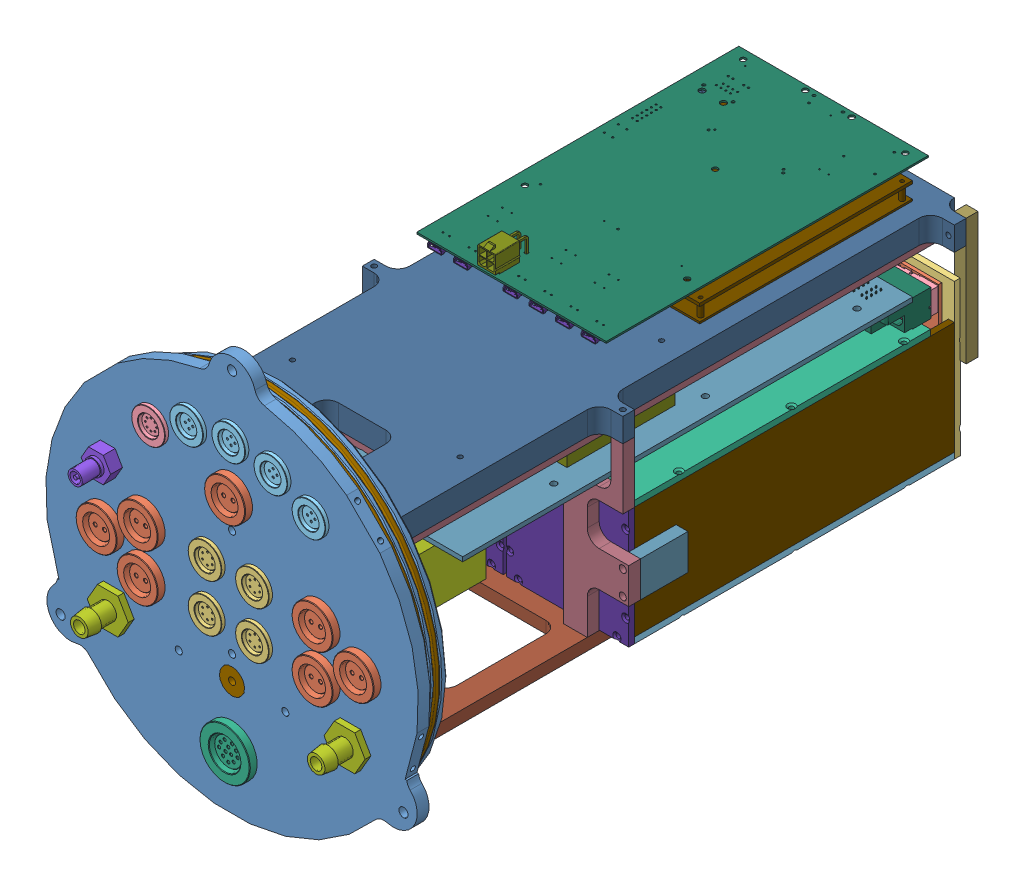
SolidWorks assembly internals, configuration Default. Lengths in mm.
Overall size (200.03 212.72 348.62).
189 component instances, 49 part files, 118 mates.
Components (placement in the parent):
- back_endcap-1: back_endcap [Default] at (-10.7708 -8.7171 12.0542) size (200.03 212.72 22.23)
- 104-DEE Connector (2 pin)-1: 104-DEE Connector (2 pin) [Default] at (36.1252 -21.4171 18.4042) size (22 22 24)
- 104-DEE Connector (2 pin)-2: 104-DEE Connector (2 pin) [Default] at (36.1252 3.9829 18.4042) size (22 22 24)
- 104-DEE Connector (2 pin)-3: 104-DEE Connector (2 pin) [Default] at (58.1223 -8.7171 18.4042) size (22 22 24)
- 104-DEE Connector (2 pin)-4: 104-DEE Connector (2 pin) [Default] at (-57.6668 3.9829 18.4042) size (22 22 24)
- 104-DEE Connector (2 pin)-5: 104-DEE Connector (2 pin) [Default] at (-57.6668 -21.4171 18.4042) size (22 22 24)
- 104-DEE Connector (2 pin)-6: 104-DEE Connector (2 pin) [Default] at (-79.6638 -8.7171 18.4042) size (22 22 24)
- 103-DEE Connector (6 pin)-1: 103-DEE Connector (6 pin) [Default] at (-23.4708 3.9829 18.4042) size (19.63 18 21)
- 103-DEE Connector (6 pin)-2: 103-DEE Connector (6 pin) [Default] at (1.9292 3.9829 18.4042) size (19.63 18 21)
- 103-DEE Connector (6 pin)-3: 103-DEE Connector (6 pin) [Default] at (-23.4708 -21.4171 18.4042) size (19.63 18 21)
- 103-DEE Connector (6 pin)-4: 103-DEE Connector (6 pin) [Default] at (1.9292 -21.4171 18.4042) size (19.63 18 21)
- 103-DEE Connector (8 pin)-1: 103-DEE Connector (8 pin) [Default] at (-53.7619 51.0956 18.4042) size (19.63 18 21)
- 103-DEE Connector (4 pin)-1: 103-DEE Connector (4 pin) [Default] at (32.2204 51.0956 18.4042) size (19.63 18 18)
- 103-DEE Connector (4 pin)-2: 103-DEE Connector (4 pin) [Default] at (11.8123 61.3957 18.4042) size (19.63 18 18)
- 103-DEE Connector (4 pin)-3: 103-DEE Connector (4 pin) [Default] at (-33.3539 61.3957 18.4042) size (19.63 18 18)
- 103-DEE Connector (4 pin)-4: 103-DEE Connector (4 pin) [Default] at (-10.7708 64.9429 18.4042) size (19.63 18 18)
- 104-DEE Connector (2 pin)-7: 104-DEE Connector (2 pin) [Default] at (-10.7708 39.2402 18.4042) size (22 22 24)
- 105-DEE Connector-1: 105-DEE Connector [Default] at (-10.7708 -78.5671 18.4042) size (28.87 27 29)
- endcap_coolant_plugs-1: endcap_coolant_plugs [Default] at (-74.2708 -44.2771 21.5792) x (0.866025 -0.5 0) z (-0.5 -0.866025 0) size (19.05 50.16 22)
- endcap_coolant_plugs-2: endcap_coolant_plugs [Default] at (52.7292 -44.2771 21.5792) x (0.866025 -0.5 0) z (-0.5 -0.866025 0) size (19.05 50.16 22)
- schradervalve-1: schradervalve [Default] at (-77.4458 23.0329 26.3417) size (15.84 13.72 33.34)
- hull o-ring-1: hull o-ring [Default] at (-10.7708 -8.7171 7.6583) size (187.32 187.32 3.17)
- hull o-ring-2: hull o-ring [Default] at (-10.7708 -8.7171 1.8023) size (187.32 187.32 3.17)
- cooling_base2-1: cooling_base2 [Default] at (-10.7708 41.1939 -159.3958) x (-1 0 0) z (0 0 1) size (139.7 12.7 323.85)
- backplane-1: backplane [Default] at (-10.7721 60.2939 -184.7958) x (0 0 1) z (-1 0 0) size (292.1 21.3 114.3) (hidden)
- cooling_mount_left-4: cooling_mount_left [Default] at (-48.8708 25.3189 8.8792) x (-1 0 0) z (0 0 1) size (38.1 12.7 12.7)
- cooling_mount_right-3: cooling_mount_right [Default] at (27.3292 25.3189 8.8792) x (-1 0 0) z (0 0 1) size (38.1 12.7 12.7)
- cooling_lid-1: cooling_lid [Default] at (-10.7708 28.4939 -159.3958) x (-1 0 0) z (0 0 1) size (114.3 3.39 304.8)
- powerboard-2: powerboard [Default] at (-16.1767 8.5021 -175.4049) x (0 0 1) z (1 0 0) size (251.08 27.63 127)
  - powerboard-1: powerboard [Default] at (-6.0888 -4.1168 5.4059) size (241.3 2.36 127)
  - molex_connector_876061001-1: molex_connector_876061001 [Default] at (-117.4688 -3.7646 44.4509) x (0 0 1) z (-1 0 0) size (48.91 16 23.62)
  - molex_connector_876061001-2: molex_connector_876061001 [Default] at (-117.4688 -3.7646 -22.8591) x (0 0 1) z (-1 0 0) size (48.91 16 23.62)
  - DC-DC-1: DC-DC [Default] at (35.2707 -4.1168 24.9416) x (1 0 0) z (0 0 -1) size (57.9 12.7 61)
- battbox-1: battbox [Default] at (51.374 -76.7142 -209.1378) x (-1 0 0) z (0 0 -1) size (65.53 82.72 178.14)
  - battbox_back-1: battbox_back [Default] at (28.2408 39.3364 -78.3001) x (-1 0 0) z (0 -1 0) size (65.53 3.34 66.67)
  - battbox_side-1: battbox_side [Default] at (-1.3502 39.3364 7.4249) x (0 1 0) z (0 0 1) size (60.32 3.17 171.45)
  - battbox_side-2: battbox_side [Default] at (57.8318 39.3364 7.4249) x (0 -1 0) z (0 0 1) size (60.32 3.17 171.45)
  - LiPoBattery-3.7V-1: LiPoBattery-3.7V [Default] at (28.1498 14.4989 -78.3001) x (0 -1 0) z (0 0 1) size (10 59 155)
  - LiPoBattery-3.7V-2: LiPoBattery-3.7V [Default] at (28.1498 24.4989 -78.3001) x (0 1 0) z (0 0 1) size (10 59 155)
  - LiPoBattery-3.7V-3: LiPoBattery-3.7V [Default] at (28.1498 54.4989 -78.3001) x (0 1 0) z (0 0 1) size (10 59 155)
  - LiPoBattery-3.7V-4: LiPoBattery-3.7V [Default] at (28.1498 34.4989 -78.3001) x (0 1 0) z (0 0 1) size (10 59 155)
  - LiPoBattery-3.7V-5: LiPoBattery-3.7V [Default] at (28.1498 44.4989 -78.3001) x (0 1 0) z (0 0 1) size (10 59 155)
  - LiPoBattery-3.7V-6: LiPoBattery-3.7V [Default] at (28.1498 64.4989 -78.3001) x (0 1 0) z (0 0 1) size (10 59 155)
  - battery_board-1: battery_board [Default] at (28.1498 47.6739 87.8159) size (59 79 1.78)
  - battbox_front-1: battbox_front [Default] at (28.2408 39.3364 93.1499) x (1 0 0) z (0 -1 0) size (65.53 3.34 82.55)
  - molex_connector_876951001-1: molex_connector_876951001 [Default] at (23.0998 81.4859 81.4659) x (1 0 0) z (0 1 0) size (48.9 20.45 12.09)
  - battbox_base-3: battbox_base [Default] at (28.2408 9.1739 7.4249) x (-1 0 0) z (0 0 1) size (65.53 3.34 171.45)
  - battbox_top-2: battbox_top [Default] at (28.2408 69.4989 1.0749) size (65.53 3.34 158.75)
- battbox-2: battbox [Default] at (-15.936 -76.7142 -209.1378) x (-1 0 0) z (0 0 -1) size (65.53 82.72 178.14)
  - battbox_back-1: battbox_back [Default] at (28.2408 39.3364 -78.3001) x (-1 0 0) z (0 -1 0) size (65.53 3.34 66.67)
  - battbox_side-1: battbox_side [Default] at (-1.3502 39.3364 7.4249) x (0 1 0) z (0 0 1) size (60.32 3.17 171.45)
  - battbox_side-2: battbox_side [Default] at (57.8318 39.3364 7.4249) x (0 -1 0) z (0 0 1) size (60.32 3.17 171.45)
  - LiPoBattery-3.7V-1: LiPoBattery-3.7V [Default] at (28.1498 14.4989 -78.3001) x (0 -1 0) z (0 0 1) size (10 59 155)
  - LiPoBattery-3.7V-2: LiPoBattery-3.7V [Default] at (28.1498 24.4989 -78.3001) x (0 1 0) z (0 0 1) size (10 59 155)
  - LiPoBattery-3.7V-3: LiPoBattery-3.7V [Default] at (28.1498 54.4989 -78.3001) x (0 1 0) z (0 0 1) size (10 59 155)
  - LiPoBattery-3.7V-4: LiPoBattery-3.7V [Default] at (28.1498 34.4989 -78.3001) x (0 1 0) z (0 0 1) size (10 59 155)
  - LiPoBattery-3.7V-5: LiPoBattery-3.7V [Default] at (28.1498 44.4989 -78.3001) x (0 1 0) z (0 0 1) size (10 59 155)
  - LiPoBattery-3.7V-6: LiPoBattery-3.7V [Default] at (28.1498 64.4989 -78.3001) x (0 1 0) z (0 0 1) size (10 59 155)
  - battery_board-1: battery_board [Default] at (28.1498 47.6739 87.8159) size (59 79 1.78)
  - battbox_front-1: battbox_front [Default] at (28.2408 39.3364 93.1499) x (1 0 0) z (0 -1 0) size (65.53 3.34 82.55)
  - molex_connector_876951001-1: molex_connector_876951001 [Default] at (23.0998 81.4859 81.4659) x (1 0 0) z (0 1 0) size (48.9 20.45 12.09)
  - battbox_base-3: battbox_base [Default] at (28.2408 9.1739 7.4249) x (-1 0 0) z (0 0 1) size (65.53 3.34 171.45)
  - battbox_top-2: battbox_top [Default] at (28.2408 69.4989 1.0749) size (65.53 3.34 158.75)
- pump-2: pump [Default] at (-44.8873 -70.9471 -90.7364) size (61.12 37.5 86.12)
- coolant_plugs-1: coolant_plugs [Default] at (25.7417 22.1439 -24.7758) x (-0.99483 0 0.101556) z (0.101556 0 0.99483) size (15.95 24.13 18.41)
- coolant_plugs-2: coolant_plugs [Default] at (-47.2833 22.1439 -24.7758) x (-0.997358 0 0.072637) z (0.072637 0 0.997358) size (15.95 24.13 18.41)
- pressure sensor-1: pressure sensor [Default] at (-10.7708 -46.8171 7.7362) x (0.998621 0.052498 0) z (0 0 1) size (18.33 15.88 86.31)
- half inch wide L bracket-1: half inch wide L bracket [Default] at (33.6792 -70.9471 12.0542) size (12.7 15.88 19.05)
- half inch wide L bracket-2: half inch wide L bracket [Default] at (-55.2208 -70.9471 12.0542) size (12.7 15.88 19.05)
- battery mount base-1: battery mount base [Default] at (-10.7708 -77.2971 -149.8708) x (0 0 -1) z (1 0 0) size (323.85 6.35 101.6)
- batter mount front-1: batter mount front [Default] at (-10.7708 -14.8766 -311.7958) x (0 1 0) z (1 0 0) size (118.49 6.35 139.7)
- batter mount back-1: batter mount back [Default] at (-10.7708 -21.2266 -127.6458) x (0 1 0) z (1 0 0) size (99.44 6.35 146.05)
- batter holding block-1: batter holding block [Default] at (-77.4458 -36.0221 -140.3458) x (0 0 1) z (0 -1 0) size (25.4 6.35 19.05)
- batter holding block-2: batter holding block [Default] at (62.2542 -36.0221 -140.3458) x (0 0 1) z (0 -1 0) size (25.4 6.35 19.05)
- batter holding block-3: batter holding block [Default] at (-10.7708 -4.1451 -140.3458) x (0 0 1) z (-1 0 0) size (25.4 6.35 19.05)
- PCB-1: PCB [Default] at (113.5642 61.2905 -17.2808) x (0 0 -1) z (0 1 0) size (172.72 101.6 16.27)
  - Revised Board-1: Revised Board [Default] at (0 0 -0.8966) size (172.72 101.6 0.91)
  - FB5-1: FB5 [Default] at origin
    - 506292128-1: 506292128 [Default] at (256.667 117.094 0.0127)
      - Extruded-1: Extruded [Default] at origin (suppressed, hidden)
  - SATA1-1: SATA1 [Default] at origin size (56.51 47.45 7.82) (suppressed, hidden)
  - FB12-1: FB12 [Default] at origin
    - 506292128-1: 506292128 [Default] at (285.75 103.124 0.0127)
      - Extruded-1: Extruded [Default] at origin (suppressed, hidden)
  - POWER-1: POWER [Default] at origin size (19.94 10 15)
    - 039300040-1: 039300040 [Default] at (114.9497 138.4306 0.0127) x (0 -1 0) z (-1 0 0) size (10 15 19.94)
      - Open CASCADE STEP translator 6.2 18.5.1.1-1: Open CASCADE STEP translator 6.2 18.5.1.1 [Default] at origin size (10 15 19.94)
  - BATTERY-1: BATTERY [Default] at origin
    - 506290848-1: 506290848 [Default] at (264.16 79.248 0.0127)
      - Extruded_1-1: Extruded_1 [Default] at origin (suppressed, hidden)
    - 506290720-1: 506290720 [Default] at (264.16 78.994 0.0127)
      - Extruded_2-1: Extruded_2 [Default] at origin (suppressed, hidden)
    - 506290592-1: 506290592 [Default] at (264.16 87.63 7.9629)
      - Extruded_3-1: Extruded_3 [Default] at origin (suppressed, hidden)
    - 506291360-1: 506291360 [Default] at (264.16 90.17 0.0127)
      - Extruded_4-1: Extruded_4 [Default] at origin (suppressed, hidden)
    - 506291232-1: 506291232 [Default] at (264.16 90.17 0.0127)
      - Extruded_5-1: Extruded_5 [Default] at origin (suppressed, hidden)
  - Reset-1: Reset [Default] at origin size (6.25 6.25 5) (suppressed, hidden)
  - FB6-1: FB6 [Default] at origin
    - 506292128-1: 506292128 [Default] at (261.747 117.094 0.0127)
      - Extruded-1: Extruded [Default] at origin (suppressed, hidden)
  - FB7-1: FB7 [Default] at origin
    - 506292128-1: 506292128 [Default] at (266.827 117.094 0.0127)
      - Extruded-1: Extruded [Default] at origin (suppressed, hidden)
  - FB8-1: FB8 [Default] at origin
    - 506292128-1: 506292128 [Default] at (269.24 132.08 0.0127)
      - Extruded-1: Extruded [Default] at origin (suppressed, hidden)
  - FB9-1: FB9 [Default] at origin
    - 506292128-1: 506292128 [Default] at (264.16 139.7 0.0127)
      - Extruded-1: Extruded [Default] at origin (suppressed, hidden)
  - FB10-1: FB10 [Default] at origin
    - 506292128-1: 506292128 [Default] at (261.62 132.08 0.0127)
      - Extruded-1: Extruded [Default] at origin (suppressed, hidden)
  - FB11-1: FB11 [Default] at origin
    - 506292128-1: 506292128 [Default] at (256.54 132.08 0.0127)
      - Extruded-1: Extruded [Default] at origin (suppressed, hidden)
  - U1-1: U1 [Default] at origin size (3.9 8.65 1.75) (suppressed, hidden)
  - VGA1-1: VGA1 [Default] at origin size (22.01 30.8 16) (suppressed, hidden)
  - X1-1: X1 [Default] at origin
    - 506290976-1: 506290976 [Default] at (259.2025 158.75 0.0127)
      - Extruded_10-1: Extruded_10 [Default] at origin (suppressed, hidden)
  - FB1_1-1: FB1_1 [Default] at origin
    - 506292000-1: 506292000 [Default] at (132.08 80.01 -1.8466)
      - Extruded_11-1: Extruded_11 [Default] at origin (suppressed, hidden)
  - FB1_2-1: FB1_2 [Default] at origin
    - 506292000-1: 506292000 [Default] at (132.08 107.95 -1.8466)
      - Extruded_11-1: Extruded_11 [Default] at origin (suppressed, hidden)
  - FB1_3-1: FB1_3 [Default] at origin
    - 506291872-1: 506291872 [Default] at (132.08 148.59 -1.8466)
      - Extruded_12-1: Extruded_12 [Default] at origin (suppressed, hidden)
  - FB2_1-1: FB2_1 [Default] at origin
    - 506292000-1: 506292000 [Default] at (132.08 88.9 -1.8466)
      - Extruded_11-1: Extruded_11 [Default] at origin (suppressed, hidden)
  - FB2_2-1: FB2_2 [Default] at origin
    - 506291872-1: 506291872 [Default] at (132.08 116.84 -1.8466)
      - Extruded_12-1: Extruded_12 [Default] at origin (suppressed, hidden)
  - FB2_3-1: FB2_3 [Default] at origin
    - 506291872-1: 506291872 [Default] at (132.08 156.21 -1.8466)
      - Extruded_12-1: Extruded_12 [Default] at origin (suppressed, hidden)
  - FB3_1-1: FB3_1 [Default] at origin
    - 506292000-1: 506292000 [Default] at (132.08 93.98 -1.8466)
      - Extruded_11-1: Extruded_11 [Default] at origin (suppressed, hidden)
  - FB3_2-1: FB3_2 [Default] at origin
    - 506291872-1: 506291872 [Default] at (132.08 121.92 -1.8466)
      - Extruded_12-1: Extruded_12 [Default] at origin (suppressed, hidden)
  - FB3_3-1: FB3_3 [Default] at origin
    - 506291872-1: 506291872 [Default] at (132.08 162.56 -1.8466)
      - Extruded_12-1: Extruded_12 [Default] at origin (suppressed, hidden)
  - FB4_1-1: FB4_1 [Default] at origin
    - 506292128-1: 506292128 [Default] at (128.27 100.33 -1.8466)
      - Extruded-1: Extruded [Default] at origin (suppressed, hidden)
  - FB4_2-1: FB4_2 [Default] at origin
    - 506291872-1: 506291872 [Default] at (132.08 129.54 -1.8466)
      - Extruded_12-1: Extruded_12 [Default] at origin (suppressed, hidden)
  - FB4_3-1: FB4_3 [Default] at origin
    - 506292000-1: 506292000 [Default] at (132.334 170.18 -1.8466)
      - Extruded_11-1: Extruded_11 [Default] at origin (suppressed, hidden)
  - IC1_1-1: IC1_1 [Default] at origin
    - 506291488-1: 506291488 [Default] at (154.94 101.6 -2.6266)
      - Extruded_13-1: Extruded_13 [Default] at origin (suppressed, hidden)
  - IC1_2-1: IC1_2 [Default] at origin
    - 506291488-1: 506291488 [Default] at (154.94 118.11 -2.6266)
      - Extruded_13-1: Extruded_13 [Default] at origin (suppressed, hidden)
  - IC1_3-1: IC1_3 [Default] at origin
    - 506291744-1: 506291744 [Default] at (158.75 156.21 -2.6266)
      - Extruded_14-1: Extruded_14 [Default] at origin (suppressed, hidden)
  - J1-1: J1 [Default] at origin size (9 9.9 4.47)
    - UX60-MB-5ST_1-1: UX60-MB-5ST_1 [Default] at (163.2375 87.52 43.1834) x (-1 0 0) z (0 -1 0) size (9 4.47 9.9)
      - ux60-mb-5sT-1: ux60-mb-5sT [Default] at (39.3275 -4.7664 57.125) x (0 0 -1) z (1 0 0) size (9.9 4.47 9)
  - J2-1: J2 [Default] at origin size (9 9.9 4.47)
    - UX60-MB-5ST_1-1: UX60-MB-5ST_1 [Default] at (163.2375 101.363 43.1834) x (-1 0 0) z (0 -1 0) size (9 4.47 9.9)
      - ux60-mb-5sT-1: ux60-mb-5sT [Default] at (39.3275 -4.7664 57.125) x (0 0 -1) z (1 0 0) size (9.9 4.47 9)
  - J3-1: J3 [Default] at origin size (9 9.9 4.47)
    - UX60-MB-5ST_1-1: UX60-MB-5ST_1 [Default] at (163.2375 115.46 43.1834) x (-1 0 0) z (0 -1 0) size (9 4.47 9.9)
      - ux60-mb-5sT-1: ux60-mb-5sT [Default] at (39.3275 -4.7664 57.125) x (0 0 -1) z (1 0 0) size (9.9 4.47 9)
  - J4-1: J4 [Default] at origin size (9 9.9 4.47)
    - UX60-MB-5ST_1-1: UX60-MB-5ST_1 [Default] at (163.2375 129.43 43.1834) x (-1 0 0) z (0 -1 0) size (9 4.47 9.9)
      - ux60-mb-5sT-1: ux60-mb-5sT [Default] at (39.3275 -4.7664 57.125) x (0 0 -1) z (1 0 0) size (9.9 4.47 9)
  - J5-1: J5 [Default] at origin size (9 9.9 4.47)
    - UX60-MB-5ST_1-1: UX60-MB-5ST_1 [Default] at (163.2375 156.1 43.1834) x (-1 0 0) z (0 -1 0) size (9 4.47 9.9)
      - ux60-mb-5sT-1: ux60-mb-5sT [Default] at (39.3275 -4.7664 57.125) x (0 0 -1) z (1 0 0) size (9.9 4.47 9)
  - J6-1: J6 [Default] at origin size (9 9.9 4.47)
    - UX60-MB-5ST_1-1: UX60-MB-5ST_1 [Default] at (163.2375 170.07 43.1834) x (-1 0 0) z (0 -1 0) size (9 4.47 9.9)
      - ux60-mb-5sT-1: ux60-mb-5sT [Default] at (39.3275 -4.7664 57.125) x (0 0 -1) z (1 0 0) size (9.9 4.47 9)
  - OR1-1: OR1 [Default] at origin
    - 506292384-1: 506292384 [Default] at (157.48 137.16 -1.9966)
      - Extruded_15-1: Extruded_15 [Default] at origin (suppressed, hidden)
- XTX-1: XTX [Default] at (-10.7708 50.7939 -241.9208) x (0 0 1) z (1 0 0) size (114 19.1 95)
Mates (geometry in assembly coordinates):
- Coincident1: coincident anti-aligned: plane of back_endcap-1 through (-10.7708 -8.7171 18.4042) normal (0 0 1); plane of 104-DEE Connector (2 pin)-4 through (-57.6668 3.9829 18.4042) normal (0 0 -1)
- Coincident2: coincident anti-aligned: plane of back_endcap-1 through (-10.7708 -8.7171 18.4042) normal (0 0 1); plane of 104-DEE Connector (2 pin)-2 through (36.1252 3.9829 18.4042) normal (0 0 -1)
- Coincident3: coincident anti-aligned: plane of back_endcap-1 through (-10.7708 -8.7171 18.4042) normal (0 0 1); plane of 104-DEE Connector (2 pin)-3 through (58.1223 -8.7171 18.4042) normal (0 0 -1)
- Coincident6: coincident anti-aligned: plane of back_endcap-1 through (-10.7708 -8.7171 18.4042) normal (0 0 1); plane of 104-DEE Connector (2 pin)-5 through (-57.6668 -21.4171 18.4042) normal (0 0 -1)
- Coincident7: coincident anti-aligned: plane of back_endcap-1 through (-10.7708 -8.7171 18.4042) normal (0 0 1); plane of 104-DEE Connector (2 pin)-6 through (-79.6638 -8.7171 18.4042) normal (0 0 -1)
- Coincident8: coincident anti-aligned: plane of back_endcap-1 through (-10.7708 -8.7171 18.4042) normal (0 0 1); plane of 104-DEE Connector (2 pin)-1 through (36.1252 -21.4171 18.4042) normal (0 0 -1)
- Concentric1: concentric aligned: cylinder of back_endcap-1 through (-79.6638 -8.7171 -3.8208) axis (0 0 1) radius 8.05; cylinder of 104-DEE Connector (2 pin)-6 through (-79.6638 -8.7171 -1.5958) axis (0 0 1) radius 8
- Concentric2: concentric aligned: cylinder of back_endcap-1 through (-57.6668 3.9829 -3.8208) axis (0 0 1) radius 8.05; cylinder of 104-DEE Connector (2 pin)-4 through (-57.6668 3.9829 -1.5958) axis (0 0 1) radius 8
- Concentric3: concentric aligned: cylinder of back_endcap-1 through (-57.6668 -21.4171 -3.8208) axis (0 0 1) radius 8.05; cylinder of 104-DEE Connector (2 pin)-5 through (-57.6668 -21.4171 -1.5958) axis (0 0 1) radius 8
- Concentric4: concentric aligned: cylinder of back_endcap-1 through (36.1252 -21.4171 -3.8208) axis (0 0 1) radius 8.05; cylinder of 104-DEE Connector (2 pin)-1 through (36.1252 -21.4171 -1.5958) axis (0 0 1) radius 8
- Concentric5: concentric aligned: cylinder of back_endcap-1 through (36.1252 3.9829 -3.8208) axis (0 0 1) radius 8.05; cylinder of 104-DEE Connector (2 pin)-2 through (36.1252 3.9829 -1.5958) axis (0 0 1) radius 8
- Concentric6: concentric aligned: cylinder of back_endcap-1 through (58.1223 -8.7171 -3.8208) axis (0 0 1) radius 8.05; cylinder of 104-DEE Connector (2 pin)-3 through (58.1223 -8.7171 -1.5958) axis (0 0 1) radius 8
- Parallel1: parallel aligned: plane of 104-DEE Connector (2 pin)-2 through (30.6404 -5.5171 4.4042) normal (0 -1 0); plane of 104-DEE Connector (2 pin)-4 through (-63.1516 -5.5171 4.4042) normal (0 -1 0)
- Parallel2: parallel aligned: plane of 104-DEE Connector (2 pin)-5 through (-63.1516 -30.9171 4.4042) normal (0 -1 0); plane of 104-DEE Connector (2 pin)-6 through (-85.1487 -18.2171 4.4042) normal (0 -1 0)
- Parallel3: parallel aligned: plane of 104-DEE Connector (2 pin)-4 through (-63.1516 -5.5171 4.4042) normal (0 -1 0); plane of 104-DEE Connector (2 pin)-6 through (-85.1487 -18.2171 4.4042) normal (0 -1 0)
- Parallel4: parallel aligned: plane of 104-DEE Connector (2 pin)-1 through (30.6404 -30.9171 4.4042) normal (0 -1 0); plane of 104-DEE Connector (2 pin)-3 through (52.6375 -18.2171 4.4042) normal (0 -1 0)
- Parallel5: parallel aligned: plane of 104-DEE Connector (2 pin)-2 through (30.6404 -5.5171 4.4042) normal (0 -1 0); plane of 104-DEE Connector (2 pin)-3 through (52.6375 -18.2171 4.4042) normal (0 -1 0)
- Perpendicular1: perpendicular: line of back_endcap-1 through (-10.7708 -8.7171 18.4042) axis (0 1 0); line of 104-DEE Connector (2 pin)-2 through (41.6101 -5.5171 7.4042) axis (-1 0 0)
- Coincident16: coincident anti-aligned: plane of back_endcap-1 through (-10.7708 -8.7171 18.4042) normal (0 0 1); plane of 103-DEE Connector (6 pin)-2 through (1.9292 3.9829 18.4042) normal (0 0 -1)
- Coincident17: coincident anti-aligned: plane of back_endcap-1 through (-10.7708 -8.7171 18.4042) normal (0 0 1); plane of 103-DEE Connector (6 pin)-1 through (-23.4708 3.9829 18.4042) normal (0 0 -1)
- Coincident18: coincident anti-aligned: plane of back_endcap-1 through (-10.7708 -8.7171 18.4042) normal (0 0 1); plane of 103-DEE Connector (6 pin)-3 through (-23.4708 -21.4171 18.4042) normal (0 0 -1)
- Coincident19: coincident anti-aligned: plane of back_endcap-1 through (-10.7708 -8.7171 18.4042) normal (0 0 1); plane of 103-DEE Connector (6 pin)-4 through (1.9292 -21.4171 18.4042) normal (0 0 -1)
- Concentric7: concentric aligned: cylinder of back_endcap-1 through (1.9292 3.9829 -3.8208) axis (0 0 1) radius 7.05; cylinder of 103-DEE Connector (6 pin)-2 through (1.9292 3.9829 -0.5958) axis (0 0 1) radius 7
- Concentric8: concentric aligned: cylinder of back_endcap-1 through (-23.4708 3.9829 -3.8208) axis (0 0 1) radius 7.05; cylinder of 103-DEE Connector (6 pin)-1 through (-23.4708 3.9829 -0.5958) axis (0 0 1) radius 7
- Concentric9: concentric aligned: cylinder of back_endcap-1 through (-23.4708 -21.4171 -3.8208) axis (0 0 1) radius 7.05; cylinder of 103-DEE Connector (6 pin)-3 through (-23.4708 -21.4171 -0.5958) axis (0 0 1) radius 7
- Concentric10: concentric aligned: cylinder of back_endcap-1 through (1.9292 -21.4171 -3.8208) axis (0 0 1) radius 7.05; cylinder of 103-DEE Connector (6 pin)-4 through (1.9292 -21.4171 -0.5958) axis (0 0 1) radius 7
- Parallel6: parallel aligned: plane of 103-DEE Connector (6 pin)-1 through (-28.3783 -4.5171 3.4042) normal (0 -1 0); plane of 103-DEE Connector (6 pin)-2 through (-2.9783 -4.5171 3.4042) normal (0 -1 0)
- Parallel7: parallel aligned: plane of 103-DEE Connector (6 pin)-3 through (-28.3783 -29.9171 3.4042) normal (0 -1 0); plane of 103-DEE Connector (6 pin)-4 through (-2.9783 -29.9171 3.4042) normal (0 -1 0)
- Parallel8: parallel: plane of 103-DEE Connector (6 pin)-1 through (-28.3783 -4.5171 3.4042) normal (0 -1 0); line of 103-DEE Connector (6 pin)-3 through (-18.5633 -29.9171 3.4042) axis (-1 0 0)
- Parallel9: parallel aligned: plane of 104-DEE Connector (2 pin)-4 through (-63.1516 -5.5171 4.4042) normal (0 -1 0); plane of 103-DEE Connector (6 pin)-1 through (-28.3783 -4.5171 3.4042) normal (0 -1 0)
- Coincident24: coincident anti-aligned: plane of back_endcap-1 through (-10.7708 -8.7171 18.4042) normal (0 0 1); plane of 103-DEE Connector (8 pin)-1 through (-53.7619 51.0956 18.4042) normal (0 0 -1)
- Concentric11: concentric aligned: cylinder of back_endcap-1 through (-53.7619 51.0956 -3.8208) axis (0 0 1) radius 7.05; cylinder of 103-DEE Connector (8 pin)-1 through (-53.7619 51.0956 -0.5958) axis (0 0 1) radius 7
- Parallel10: parallel aligned: plane of 103-DEE Connector (4 pin)-1 through (37.1278 59.5956 6.4042) normal (0 1 0); plane of 103-DEE Connector (4 pin)-2 through (16.7198 69.8957 6.4042) normal (0 1 0)
- Parallel11: parallel aligned: plane of 103-DEE Connector (4 pin)-2 through (16.7198 69.8957 6.4042) normal (0 1 0); plane of 103-DEE Connector (4 pin)-3 through (-28.4464 69.8957 6.4042) normal (0 1 0)
- Parallel12: parallel aligned: plane of 103-DEE Connector (4 pin)-3 through (-28.4464 69.8957 6.4042) normal (0 1 0); plane of 103-DEE Connector (4 pin)-4 through (-5.8633 73.4429 6.4042) normal (0 1 0)
- Parallel13: parallel aligned: plane of 104-DEE Connector (2 pin)-6 through (-74.179 0.7829 4.4042) normal (0 1 0); plane of 103-DEE Connector (4 pin)-4 through (-5.8633 73.4429 6.4042) normal (0 1 0)
- Concentric14: concentric aligned: cylinder of back_endcap-1 through (-33.3539 61.3957 -3.8208) axis (0 0 1) radius 7.05; cylinder of 103-DEE Connector (4 pin)-3 through (-33.3539 61.3957 2.4042) axis (0 0 1) radius 7
- Concentric15: concentric aligned: cylinder of back_endcap-1 through (11.8123 61.3957 -3.8208) axis (0 0 1) radius 7.05; cylinder of 103-DEE Connector (4 pin)-2 through (11.8123 61.3957 2.4042) axis (0 0 1) radius 7
- Concentric16: concentric aligned: cylinder of back_endcap-1 through (32.2204 51.0956 -3.8208) axis (0 0 1) radius 7.05; cylinder of 103-DEE Connector (4 pin)-1 through (32.2204 51.0956 2.4042) axis (0 0 1) radius 7
- Coincident29: coincident anti-aligned: plane of back_endcap-1 through (-10.7708 -8.7171 18.4042) normal (0 0 1); plane of 103-DEE Connector (4 pin)-2 through (11.8123 61.3957 18.4042) normal (0 0 -1)
- Coincident30: coincident anti-aligned: plane of back_endcap-1 through (-10.7708 -8.7171 18.4042) normal (0 0 1); plane of 103-DEE Connector (4 pin)-1 through (32.2204 51.0956 18.4042) normal (0 0 -1)
- Concentric17: concentric aligned: cylinder of back_endcap-1 through (-10.7708 64.9429 -3.8208) axis (0 0 1) radius 7.05; cylinder of 103-DEE Connector (4 pin)-4 through (-10.7708 64.9429 2.4042) axis (0 0 1) radius 7
- Coincident31: coincident anti-aligned: plane of back_endcap-1 through (-10.7708 -8.7171 18.4042) normal (0 0 1); plane of 103-DEE Connector (4 pin)-4 through (-10.7708 64.9429 18.4042) normal (0 0 -1)
- Parallel14: parallel: line of 104-DEE Connector (2 pin)-2 through (30.6404 13.4829 7.4042) axis (1 0 0); plane of 104-DEE Connector (2 pin)-7 through (-5.2859 48.7402 4.4042) normal (0 1 0)
- Concentric18: concentric aligned: cylinder of back_endcap-1 through (-10.7708 39.2402 -3.8208) axis (0 0 1) radius 8.05; cylinder of 104-DEE Connector (2 pin)-7 through (-10.7708 39.2402 -1.5958) axis (0 0 1) radius 8
- Coincident34: coincident anti-aligned: plane of back_endcap-1 through (-10.7708 -8.7171 18.4042) normal (0 0 1); plane of 104-DEE Connector (2 pin)-7 through (-10.7708 39.2402 18.4042) normal (0 0 -1)
- Concentric19: concentric aligned: cylinder of back_endcap-1 through (-10.7708 -78.5671 -3.8208) axis (0 0 1) radius 10.033; cylinder of 105-DEE Connector-1 through (-10.7708 -78.5671 -6.5958) axis (0 0 1) radius 10
- Coincident35: coincident anti-aligned: plane of back_endcap-1 through (-10.7708 -8.7171 18.4042) normal (0 0 1); plane of 105-DEE Connector-1 through (-10.7708 -78.5671 18.4042) normal (0 0 -1)
- Parallel15: parallel aligned: plane of 103-DEE Connector (6 pin)-3 through (-18.5633 -12.9171 3.4042) normal (0 1 0); plane of 105-DEE Connector-1 through (-3.5539 -66.0671 -0.5958) normal (0 1 0)
- Parallel16: parallel aligned: plane of 103-DEE Connector (6 pin)-2 through (6.8367 12.4829 3.4042) normal (0 1 0); plane of endcap_coolant_plugs-2 through (58.2285 -34.7521 18.4042) normal (0 1 0)
- Parallel17: parallel aligned: plane of 103-DEE Connector (6 pin)-3 through (-18.5633 -12.9171 3.4042) normal (0 1 0); plane of endcap_coolant_plugs-1 through (-68.7715 -34.7521 18.4042) normal (0 1 0)
- Concentric20: concentric anti-aligned: cylinder of back_endcap-1 through (-74.2708 -44.2771 -3.8208) axis (0 0 1) radius 5.588; cylinder of endcap_coolant_plugs-1 through (-74.2708 -44.2771 19.9917) axis (0 0 -1) radius 5.588
- Concentric21: concentric anti-aligned: cylinder of back_endcap-1 through (52.7292 -44.2771 -3.8208) axis (0 0 1) radius 5.588; cylinder of endcap_coolant_plugs-2 through (52.7292 -44.2771 19.9917) axis (0 0 -1) radius 5.588
- Coincident39: coincident anti-aligned: plane of back_endcap-1 through (-10.7708 -8.7171 18.4042) normal (0 0 1); plane of endcap_coolant_plugs-2 through (36.2314 -34.7521 18.4042) normal (0 0 -1)
- Coincident40: coincident anti-aligned: plane of back_endcap-1 through (-10.7708 -8.7171 18.4042) normal (0 0 1); plane of endcap_coolant_plugs-1 through (-90.7686 -34.7521 18.4042) normal (0 0 -1)
- Concentric22: concentric aligned: cone of back_endcap-1 through (-77.4458 23.0329 12.0542) axis (0 0 1); cylinder of schradervalve-1 through (-77.4458 23.0329 2.5292) axis (0 0 1) radius 4.9276
- Coincident41: coincident anti-aligned: plane of back_endcap-1 through (-10.7708 -8.7171 18.4042) normal (0 0 1); plane of schradervalve-1 through (-73.4863 29.8909 18.4042) normal (0 0 -1)
- Concentric23: concentric anti-aligned: cylinder of back_endcap-1 through (-10.7708 -8.7171 12.0542) axis (0 0 1) radius 91.1225; cylinder of hull o-ring-2 through (-10.7708 -8.7171 1.8023) axis (0 0 -1) radius 90.4875
- Concentric24: concentric anti-aligned: cylinder of back_endcap-1 through (-10.7708 -8.7171 12.0542) axis (0 0 1) radius 91.1225; cylinder of hull o-ring-1 through (-10.7708 -8.7171 7.6583) axis (0 0 -1) radius 90.4875
- Coincident42: coincident anti-aligned: plane of back_endcap-1 through (-10.7708 84.9454 9.2458) normal (0 0 -1); plane of hull o-ring-1 through (-10.7708 84.1834 9.2458) normal (0 0 1)
- Coincident43: coincident anti-aligned: plane of back_endcap-1 through (-10.7708 84.9454 3.3898) normal (0 0 -1); plane of hull o-ring-2 through (-10.7708 84.1834 3.3898) normal (0 0 1)
- Coincident44: coincident anti-aligned: plane of back_endcap-1 through (-10.7708 -8.7171 12.0542) normal (0 0 -1); plane of cooling_base2-1 through (8.2792 28.4939 12.0542) normal (0 0 1)
- Parallel18: parallel anti-aligned: plane of 103-DEE Connector (6 pin)-1 through (-18.5633 12.4829 3.4042) normal (0 1 0); plane of cooling_base2-1 through (46.3792 28.4939 12.0542) normal (0 -1 0)
- Parallel19: parallel: plane of cooling_base2-1 through (-67.9208 28.4939 -311.7958) normal (-1 0 0); line of backplane-1 through (-67.9221 61.8941 -311.7958) axis (0 0 1)
- Coincident60: coincident anti-aligned: plane of cooling_base2-1 through (46.3792 28.4939 12.0542) normal (0 -1 0); plane of cooling_mount_left-4 through (-67.9208 28.4939 12.0542) normal (0 1 0)
- Concentric39: concentric aligned: circle of cooling_base2-1; circle of cooling_mount_left-4
- Concentric40: concentric aligned: circle of cooling_base2-1; circle of cooling_mount_left-4
- Concentric41: concentric aligned: circle of cooling_base2-1; circle of cooling_mount_right-3
- Concentric42: concentric aligned: circle of cooling_base2-1; circle of cooling_mount_right-3
- Coincident62: coincident anti-aligned: plane of cooling_base2-1 through (46.3792 28.4939 12.0542) normal (0 -1 0); plane of cooling_mount_right-3 through (8.2792 28.4939 12.0542) normal (0 1 0)
- Coincident63: coincident anti-aligned: plane of cooling_base2-1 through (46.3792 28.4939 12.0542) normal (0 -1 0); plane of cooling_lid-1 through (46.3792 28.4939 12.0542) normal (0 1 0)
- Concentric43: concentric aligned: circle of cooling_base2-1; circle of cooling_lid-1
- Concentric44: concentric aligned: circle of cooling_base2-1; circle of cooling_lid-1
- Coincident70: coincident anti-aligned: plane of cooling_lid-1 through (46.3792 25.3189 12.0542) normal (0 -1 0); plane of powerboard-2/DC-DC-1 through (-21.7351 25.3189 -169.0842) normal (0 1 0)
- Concentric47: concentric aligned: circle of cooling_lid-1; circle of powerboard-2/powerboard-1
- Concentric48: concentric aligned: circle of cooling_lid-1; circle of powerboard-2/powerboard-1
- Coincident74: coincident aligned: plane of battbox-1/battbox_base-3 through (-9.6328 -70.7153 -302.2878) normal (0 -1 0); plane of battbox-2/battbox_base-3 through (-76.9428 -70.7153 -302.2878) normal (0 -1 0)
- Coincident75: coincident aligned: plane of battbox-1/battbox_back-1 through (-9.6328 -70.7153 -127.6628) normal (0 0 1); plane of battbox-2/battbox_back-1 through (-76.9428 -70.7153 -127.6628) normal (0 0 1)
- Parallel21: parallel aligned: plane of cooling_base2-1 through (46.3792 28.4939 12.0542) normal (1 0 0); plane of battbox-1/battbox_side-1 through (55.8992 -67.5403 -130.8378) normal (1 0 0)
- Parallel22: parallel aligned: plane of cooling_lid-1 through (46.3792 25.3189 12.0542) normal (0 -1 0); plane of battbox-1/battbox_base-3 through (-9.6328 -70.7153 -302.2878) normal (0 -1 0)
- Concentric49: concentric anti-aligned: cylinder of powerboard-2/molex_connector_876061001-1 through (48.2792 3.1967 -292.8738) axis (0 0 -1) radius 3.5; cylinder of battbox-1/molex_connector_876951001-1 through (48.2792 3.1967 -292.8738) axis (0 0 1) radius 3.375
- Coincident78: coincident anti-aligned: plane of powerboard-2/molex_connector_876061001-1 through (3.8192 3.6967 -292.8738) normal (0 0 -1); plane of battbox-1/molex_connector_876951001-1 through (44.9242 -1.2733 -292.8738) normal (0 0 1)
- Concentric51: concentric anti-aligned: cylinder of powerboard-2/molex_connector_876061001-2 through (-19.0308 3.1967 -292.8738) axis (0 0 -1) radius 3.5; cylinder of battbox-2/molex_connector_876951001-1 through (-19.0308 3.1967 -292.8738) axis (0 0 1) radius 3.375
- Concentric53: concentric aligned: circle of back_endcap-1; circle of cooling_mount_right-3
- Concentric54: concentric aligned: circle of back_endcap-1; circle of cooling_mount_left-4
- Coincident88: coincident anti-aligned: plane of cooling_lid-1 through (46.3792 25.3189 12.0542) normal (0 -1 0); plane of coolant_plugs-2 through (-38.996 25.3189 -20.7634) normal (0 1 0)
- Coincident89: coincident anti-aligned: plane of cooling_lid-1 through (46.3792 25.3189 12.0542) normal (0 -1 0); plane of coolant_plugs-1 through (34.142 25.3189 -21.0056) normal (0 1 0)
- Concentric57: concentric anti-aligned: circle of cooling_lid-1; cylinder of coolant_plugs-1 through (25.7417 6.2689 -24.7758) axis (0 1 0) radius 4.7625
- Concentric58: concentric anti-aligned: cylinder of cooling_lid-1 through (-47.2833 28.4939 -24.7758) axis (0 -1 0) radius 4.7625; cylinder of coolant_plugs-2 through (-47.2833 6.2689 -24.7758) axis (0 1 0) radius 4.7625
- Coincident98: coincident aligned: plane of back_endcap-1 through (-10.7708 -8.7171 18.4042) normal (0 0 1); plane of pressure sensor-1 through (-10.7708 -46.8171 18.4042) normal (0 0 1)
- Concentric71: concentric anti-aligned: circle of back_endcap-1; cylinder of pressure sensor-1 through (-10.7708 -46.8171 -46.8738) axis (0 0 1) radius 7.9375
- Coincident121: coincident anti-aligned: plane of back_endcap-1 through (-10.7708 -8.7171 12.0542) normal (0 0 -1); plane of half inch wide L bracket-1 through (40.0292 -70.9471 12.0542) normal (0 0 1)
- Coincident122: coincident anti-aligned: plane of back_endcap-1 through (-10.7708 -8.7171 12.0542) normal (0 0 -1); plane of half inch wide L bracket-2 through (-48.8708 -70.9471 12.0542) normal (0 0 1)
- Concentric72: concentric anti-aligned: circle of batter mount back-1; circle of batter holding block-3
- Concentric73: concentric aligned: circle of batter mount back-1; circle of batter holding block-3
- Coincident123: coincident anti-aligned: plane of batter mount back-1 through (59.0792 -70.9471 -127.6458) normal (0 0 -1); plane of batter holding block-3 through (-1.2458 2.2049 -127.6458) normal (0 0 1)
- Concentric74: concentric anti-aligned: circle of batter mount back-1; circle of batter holding block-2
- Concentric75: concentric anti-aligned: circle of batter mount back-1; circle of batter holding block-2
- Concentric76: concentric anti-aligned: circle of batter mount back-1; circle of batter holding block-1
- Concentric77: concentric anti-aligned: circle of batter mount back-1; circle of batter holding block-1
- Coincident124: coincident anti-aligned: plane of batter mount back-1 through (59.0792 -70.9471 -127.6458) normal (0 0 -1); plane of batter holding block-1 through (-83.7958 -26.4971 -127.6458) normal (0 0 1)
- Coincident125: coincident anti-aligned: plane of batter mount back-1 through (59.0792 -70.9471 -127.6458) normal (0 0 -1); plane of batter holding block-2 through (55.9042 -26.4971 -127.6458) normal (0 0 1)
- Concentric78: concentric anti-aligned: circle of battery mount base-1; circle of batter mount back-1
- Coincident126: coincident anti-aligned: plane of battery mount base-1 through (40.0292 -70.9471 12.0542) normal (0 1 0); plane of batter mount back-1 through (-80.6208 -70.9471 -121.2958) normal (0 -1 0)
- Concentric79: concentric anti-aligned: circle of battery mount base-1; circle of batter mount back-1
- Coincident127: coincident anti-aligned: plane of half inch wide L bracket-1 through (40.0292 -70.9471 -6.9958) normal (0 -1 0); plane of battery mount base-1 through (40.0292 -70.9471 12.0542) normal (0 1 0)
- Concentric80: concentric anti-aligned: circle of half inch wide L bracket-1; circle of battery mount base-1
- Concentric81: concentric anti-aligned: circle of half inch wide L bracket-2; circle of battery mount base-1
- Concentric82: concentric aligned: circle of back_endcap-1; circle of half inch wide L bracket-1
- Coincident128: coincident anti-aligned: circle of battery mount base-1; circle of batter mount front-1
- Coincident129: coincident aligned: plane of battery mount base-1 through (-61.5708 -70.9471 -311.7958) normal (0 0 -1); plane of batter mount front-1 through (59.0792 -70.9471 -311.7958) normal (0 0 -1)
- Coincident130: coincident anti-aligned: plane of pump-2 through (-75.4467 -34.4346 -121.2958) normal (0 0 -1); plane of batter mount back-1 through (59.0792 -70.9471 -121.2958) normal (0 0 1)
- Coincident131: coincident anti-aligned: plane of pump-2 through (-75.4467 -70.9471 -60.177) normal (0 -1 0); plane of battery mount base-1 through (40.0292 -70.9471 12.0542) normal (0 1 0)
- Coincident132: coincident anti-aligned: plane of cooling_base2-1 through (46.3792 41.1939 12.0542) normal (0 1 0); plane of XTX-1 through (36.7292 41.1939 -298.9208) normal (0 -1 0)
- Concentric86: concentric aligned: circle of cooling_base2-1; circle of XTX-1
- Coincident133: coincident anti-aligned: plane of cooling_base2-1 through (46.3792 41.1939 12.0542) normal (0 1 0); plane of XTX-1 through (36.7292 41.1939 -298.9208) normal (0 -1 0)
- Concentric88: concentric anti-aligned: circle of cooling_base2-1; circle of XTX-1
- Concentric89: concentric anti-aligned: circle of cooling_base2-1; circle of XTX-1
